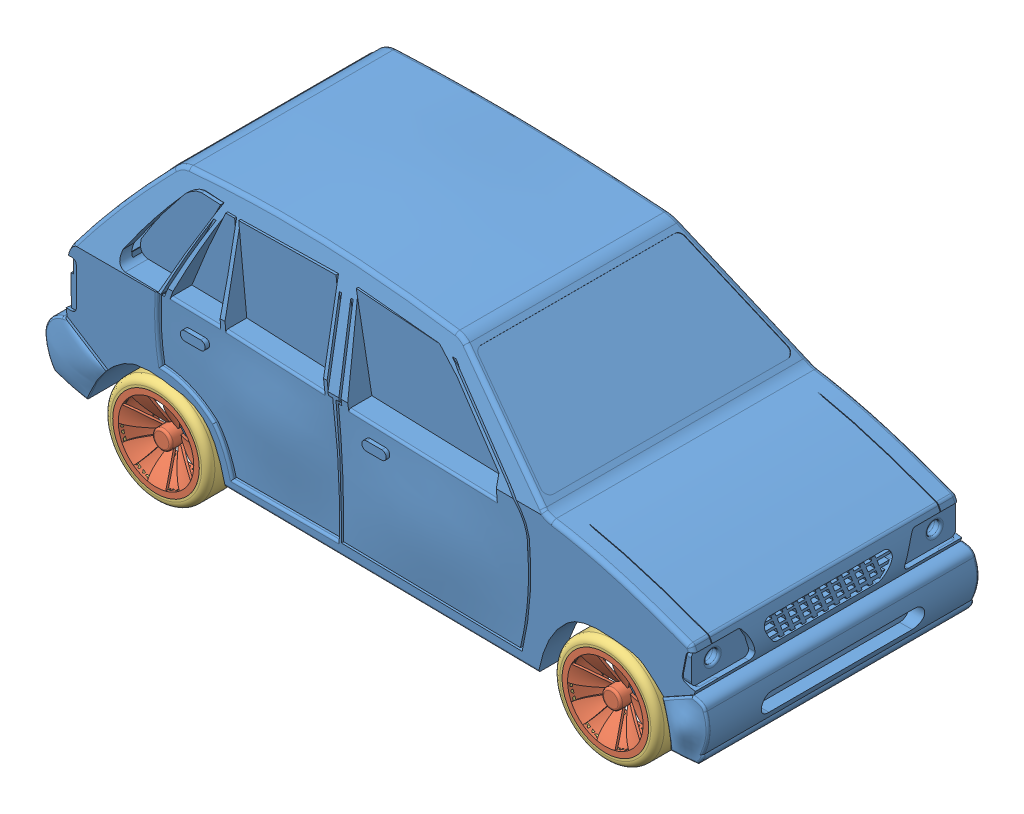
SolidWorks assembly mehran car assem, configuration Default. Lengths in mm.
Overall size (856.06 185.36 156.19).
13 component instances, 3 part files, 8 mates.
Components (placement in the parent):
- mehran car-1: mehran car [Default] at (285.9808 489.6972 764.2161) size (856.06 185.36 156.19)
- tyre car-1: tyre car [Default] at (155.5575 444.0985 711.8852) x (0 0 -1) z (1 0 0) size (17.01 47 47)
  - rim-1: rim [Default] at (-44.331 10.833 31.2224) x (0 0 -1) z (1 0 0) size (39 39 17)
  - rim oart 2-1: rim oart 2 [Default] at (-52.825 10.833 31.2224) size (17 47 47)
- tyre car-2: tyre car [Default] at (357.9641 444.0985 711.8852) x (0 0 -1) z (1 0 0) size (17.01 47 47)
  - rim-1: rim [Default] at (-44.331 10.833 31.2224) x (0 0 -1) z (1 0 0) size (39 39 17)
  - rim oart 2-1: rim oart 2 [Default] at (-52.825 10.833 31.2224) size (17 47 47)
- tyre car-3: tyre car [Default] at (420.4089 444.0985 696.5471) x (0 0 1) z (-1 0 0) size (17.01 47 47)
  - rim-1: rim [Default] at (-44.331 10.833 31.2224) x (0 0 -1) z (1 0 0) size (39 39 17)
  - rim oart 2-1: rim oart 2 [Default] at (-52.825 10.833 31.2224) size (17 47 47)
- tyre car-4: tyre car [Default] at (218.0023 444.0985 696.5471) x (0 0 1) z (-1 0 0) size (17.01 47 47)
  - rim-1: rim [Default] at (-44.331 10.833 31.2224) x (0 0 -1) z (1 0 0) size (39 39 17)
  - rim oart 2-1: rim oart 2 [Default] at (-52.825 10.833 31.2224) size (17 47 47)
Mates (geometry in assembly coordinates):
- Concentric1: concentric anti-aligned: cylinder of mehran car-1 through (186.7799 454.9315 652.2161) axis (0 0 1) radius 2.5; cylinder of tyre car-1/rim-1 through (186.7799 454.9315 761.2161) axis (0 0 -1) radius 2.5
- Coincident1: coincident aligned: circle of mehran car-1; circle of tyre car-1/rim-1
- Concentric2: concentric anti-aligned: cylinder of mehran car-1 through (389.1865 454.9315 652.2161) axis (0 0 1) radius 2.5; cylinder of tyre car-2/rim-1 through (389.1865 454.9315 761.2161) axis (0 0 -1) radius 2.5
- Coincident2: coincident aligned: circle of mehran car-1; circle of tyre car-2/rim-1
- Concentric3: concentric aligned: cylinder of mehran car-1 through (389.1865 454.9315 652.2161) axis (0 0 1) radius 2.5; cylinder of tyre car-3/rim-1 through (389.1865 454.9315 647.2161) axis (0 0 1) radius 2.5
- Coincident3: coincident anti-aligned: circle of mehran car-1; circle of tyre car-3/rim-1
- Concentric5: concentric: cylinder of mehran car-1 through (186.7799 454.9315 652.2161) axis (0 0 1) radius 2.5; cylinder of tyre car-4/rim-1 through (186.7799 454.9315 647.2161) axis (0 0 1) radius 2.5
- Coincident4: coincident anti-aligned: circle of mehran car-1; circle of tyre car-4/rim-1
